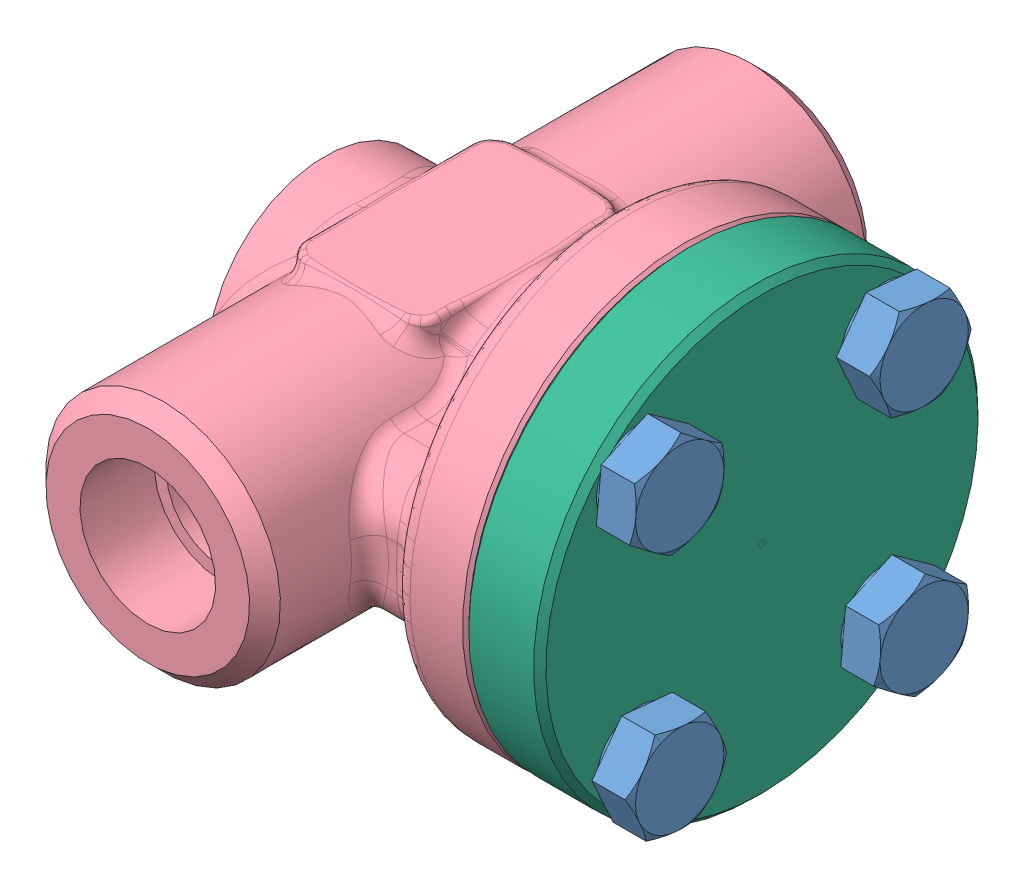
SolidWorks assembly PressureValve, configuration Default. Lengths in mm.
Overall size (82.48 101.82 101.82).
9 component instances, 6 part files, 0 mates.
Components (placement in the parent):
- BOLT-1-1: BOLT-1 [Default] at (18.48 -19.799 19.799) x (0 0.413547 -0.910483) z (0 -0.910483 -0.413547) size (14.3 32.42 16.51)
- BOLT-1-2: BOLT-1 [Default] at (18.48 -19.799 -19.799) x (0 0.910483 0.413547) z (0 0.413547 -0.910483) size (14.3 32.42 16.51)
- BOLT-1-3: BOLT-1 [Default] at (18.48 19.799 19.799) x (0 -0.910483 -0.413547) z (0 -0.413547 0.910483) size (14.3 32.42 16.51)
- BOLT-1-4: BOLT-1 [Default] at (18.48 19.799 -19.799) x (0 -0.413547 0.910483) z (0 0.910483 0.413547) size (14.3 32.42 16.51)
- DISC-1-1: DISC-1 [Default] at (-24.38 0 0) x (0 -0.413547 0.910483) z (0 0.910483 0.413547) size (24.99 17.78 24.99)
- GASKET(Compressed)-1: GASKET(Compressed) [Default] at (-4.8 0 0) x (0 -0.413547 0.910483) z (0 0.910483 0.413547) size (40 2.5 40)
- Pipe-1-1: Pipe-1 [Default] at (-37.5 0 0) x (0 0 -1) z (0 -1 0) size (100 64 72)
- spring-1-1: spring-1 [Default] at (-15.771 0 0) x (0 0 -1) z (0 -1 0) size (18.34 23.22 20.03)
- Upper Cover-1-1: Upper Cover-1 [Default] x (0 0.707107 -0.707107) z (0 -0.707107 -0.707107) size (72 12 72)
